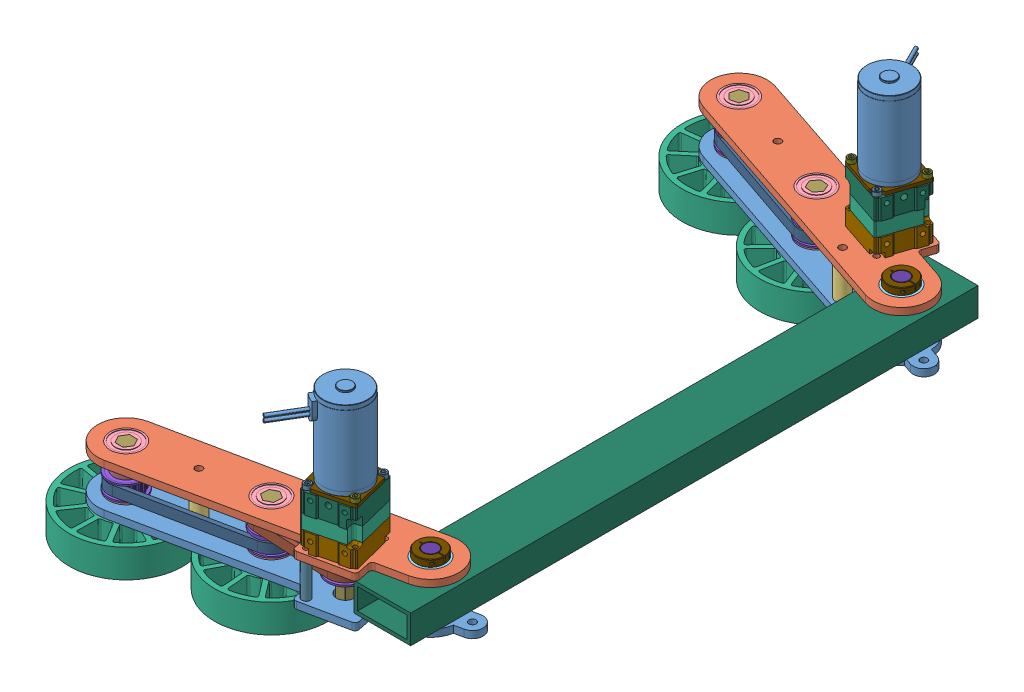
SolidWorks assembly IntakeV7Assem, configuration Default. Lengths in mm.
Overall size (333.6 194.94 656.15).
123 component instances, 36 part files, 159 mates.
Components (placement in the parent):
- IntakeV7PlateBottom-1: IntakeV7PlateBottom [Default] at (95.0249 -59.099 -418.9986) x (-0.203071 0 -0.979164) z (0.979164 0 -0.203071) size (67.49 6.35 297.21)
- IntakeV7PlateBottom-2: IntakeV7PlateBottom [Default] at (61.0398 -52.749 -268.9804) x (-0.317653 0 0.948207) z (0.948207 0 0.317653) size (67.49 6.35 297.21)
- IntakeV7PlateTop-1: IntakeV7PlateTop [Default] at (95.0249 -20.491 -418.9986) x (-0.203071 0 -0.979164) z (0.979164 0 -0.203071) size (67.49 6.35 281.33)
- IntakeV7PlateTop-2: IntakeV7PlateTop [Default] at (61.0398 -14.141 -268.9804) x (-0.317653 0 0.948207) z (0.948207 0 0.317653) size (67.49 6.35 281.33)
- PlateSpacer-1: PlateSpacer [Default] at (-344.9218 -20.491 -112.451) x (-0.978908 0 -0.204301) z (0 -1 0) size (12.7 12.7 32.26)
- PlateSpacer-2: PlateSpacer [Default] at (-227.8654 -20.491 -152.2919) x (1 0 0) z (0 -1 0) size (12.7 12.7 32.26)
- PlateSpacer-3: PlateSpacer [Default] at (-227.9763 -52.749 -572.0649) x (1 0 0) z (0 1 0) size (12.7 12.7 32.26)
- PlateSpacer-4: PlateSpacer [Default] at (-339.4879 -52.749 -625.4941) x (-0.769908 0 0.638155) z (0 1 0) size (12.7 12.7 32.26)
- HalfHexBearing-1: HalfHexBearing [Default] at (-398.7795 -14.141 -101.2813) x (0.520029 0 -0.854148) z (-0.854148 0 -0.520029) size (31.12 7.94 31.12)
- HalfHexBearing-2: HalfHexBearing [Default] at (-398.7795 -59.099 -101.2813) x (-0.520029 0 0.854148) z (-0.854148 0 -0.520029) size (31.12 7.94 31.12)
- HalfHexBearing-3: HalfHexBearing [Default] at (-291.0642 -14.141 -123.6206) x (-0.062031 0 0.998074) z (0.998074 0 0.062031) size (31.12 7.94 31.12)
- HalfHexBearing-4: HalfHexBearing [Default] at (-291.0642 -59.099 -123.6206) x (0.062031 0 -0.998074) z (0.998074 0 0.062031) size (31.12 7.94 31.12)
- HalfHexBearing-5: HalfHexBearing [Default] at (-391.6428 -14.141 -642.9662) x (-0.712674 0 -0.701495) z (-0.701495 0 0.712674) size (31.12 7.94 31.12)
- HalfHexBearing-6: HalfHexBearing [Default] at (-391.6428 -59.099 -642.9662) x (0.712674 0 0.701495) z (-0.701495 0 0.712674) size (31.12 7.94 31.12)
- HalfHexBearing-7: HalfHexBearing [Default] at (-287.333 -14.141 -608.022) x (-0.408462 0 -0.912775) z (-0.912775 0 0.408462) size (31.12 7.94 31.12)
- HalfHexBearing-8: HalfHexBearing [Default] at (-287.333 -59.099 -608.022) x (0.408462 0 0.912775) z (-0.912775 0 0.408462) size (31.12 7.94 31.12)
- HalfRoundBearing-1: HalfRoundBearing [Default] at (-173.0483 -14.141 -148.0962) x (0.837169 0 0.546944) z (0.546944 0 -0.837169) size (31.12 7.94 31.12)
- HalfRoundBearing-2: HalfRoundBearing [Default] at (-173.0483 -59.099 -148.0962) x (-0.997571 0 -0.069658) z (0.069658 0 -0.997571) size (31.12 7.94 31.12)
- HalfRoundBearing-3: HalfRoundBearing [Default] at (-173.0483 -59.099 -569.7362) x (-1 0 0) z (0 0 -1) size (31.12 7.94 31.12)
- HalfRoundBearing-4: HalfRoundBearing [Default] at (-173.0483 -14.141 -569.7362) x (0.837169 0 0.546944) z (0.546944 0 -0.837169) size (31.12 7.94 31.12)
- 4inCompliantWheel-1: 4inCompliantWheel [Default] at (-286.2135 -79.3385 -139.5879) x (0.062031 0 -0.998074) z (0 1 0) size (101.6 101.6 25.74)
  - 4IN Compliant Wheel FINAL Overmold-1: 4IN Compliant Wheel FINAL Overmold [Default] at (-16.2374 3.8509 18.652) size (101.6 101.6 25.74)
  - 2in Wheel Intergrated 0500 HEX Hub-1: 2in Wheel Intergrated 0500 HEX Hub [Default] at (-16.2374 3.8509 5.952) x (-1 0 0) z (0 0 -1) size (41.91 41.91 25.4)
- 4inCompliantWheel-2: 4inCompliantWheel [Default] at (-414.9228 -79.3385 -105.5092) x (-0.999729 0 -0.023285) z (0 1 0) size (101.6 101.6 25.74)
  - 4IN Compliant Wheel FINAL Overmold-1: 4IN Compliant Wheel FINAL Overmold [Default] at (-16.2374 3.8509 18.652) size (101.6 101.6 25.74)
  - 2in Wheel Intergrated 0500 HEX Hub-1: 2in Wheel Intergrated 0500 HEX Hub [Default] at (-16.2374 3.8509 5.952) x (-1 0 0) z (0 0 -1) size (41.91 41.91 25.4)
- 4inCompliantWheel-3: 4inCompliantWheel [Default] at (-408.3193 -79.3385 -642.3514) x (-0.96385 0 0.266447) z (0 1 0) size (101.6 101.6 25.74)
  - 4IN Compliant Wheel FINAL Overmold-1: 4IN Compliant Wheel FINAL Overmold [Default] at (-16.2374 3.8509 18.652) size (101.6 101.6 25.74)
  - 2in Wheel Intergrated 0500 HEX Hub-1: 2in Wheel Intergrated 0500 HEX Hub [Default] at (-16.2374 3.8509 5.952) x (-1 0 0) z (0 0 -1) size (41.91 41.91 25.4)
- 4inCompliantWheel-4: 4inCompliantWheel [Default] at (-299.972 -79.3385 -597.1252) x (-0.586256 0 0.810126) z (0 1 0) size (101.6 101.6 25.74)
  - 4IN Compliant Wheel FINAL Overmold-1: 4IN Compliant Wheel FINAL Overmold [Default] at (-16.2374 3.8509 18.652) size (101.6 101.6 25.74)
  - 2in Wheel Intergrated 0500 HEX Hub-1: 2in Wheel Intergrated 0500 HEX Hub [Default] at (-16.2374 3.8509 5.952) x (-1 0 0) z (0 0 -1) size (41.91 41.91 25.4)
- 18THTD9MMPulley-1: 18THTD9MMPulley [Default] at (-221.16 -29.4115 -119.9599) x (0.999849 0 0.017394) z (0 -1 0) size (32 32 14.5)
- 18THTD9MMPulley-2: 18THTD9MMPulley [Default] at (-217.4874 -29.4115 -603.3747) x (1 0 0) z (0 1 0) size (32 32 14.5)
- 18THTD9MMPulley-3: 18THTD9MMPulley [Default] at (-291.0642 -43.9115 -123.6206) x (0.746276 0 0.665636) z (0 -1 0) size (32 32 14.5)
- 18THTD9MMPulley-4: 18THTD9MMPulley [Default] at (-398.7795 -43.9115 -101.2813) x (-0.520029 0 0.854148) z (0 1 0) size (32 32 14.5)
- 18THTD9MMPulley-5: 18THTD9MMPulley [Default] at (-391.6428 -43.9115 -642.9662) x (1 0 0) z (0 1 0) size (32 32 14.5)
- 18THTD9MMPulley-6: 18THTD9MMPulley [Default] at (-287.333 -43.9115 -608.022) x (1 0 0) z (0 1 0) size (32 32 14.5)
- 18THTD9MMPulley-7: 18THTD9MMPulley [Default] at (-291.0642 -29.4115 -123.6206) x (0.20332 0 -0.979112) z (0 1 0) size (32 32 14.5)
- 18THTD9MMPulley-8: 18THTD9MMPulley [Default] at (-287.333 -29.4115 -608.022) x (1 0 0) z (0 1 0) size (32 32 14.5)
- VersaPlanetary_v2_Single_Stage_10_1_with_BAG-1: VersaPlanetary_v2_Single_Stage_10_1_with_BAG [Default] at (-215.7363 2.484 -98.4068) x (0 -1 0) z (0.969767 0 -0.244033) size (163.4 63.56 63.56)
  - 217-2625-026 Rev1-1: 217-2625-026 Rev1 [Default] at (-6.5 22.225 0) x (0 -1 0) z (-1 0 0) size (44.45 42 18.13)
  - 217-2742-001 Rev4-1: 217-2742-001 Rev4 [Default] at (0.2002 22.225 0) x (1 0 0) z (0 -0.092627 0.995701) size (7 28 28)
  - 217-2742-001 Rev4-2: 217-2742-001 Rev4 [Default] at (8.2002 22.225 0) size (7 28 28)
  - 217-2625-017 Rev1_9714K61-1: 217-2625-017 Rev1_9714K61 [Default] at (7.42 22.3002 -0.342) x (0 0.56703 0.823697) z (0 -0.823697 0.56703) size (28.51 4.98 30.18)
  - 217-2625-003 Rev1-1: 217-2625-003 Rev1 [Default] at (7.4478 22.225 0) x (0 -1 0) z (1 0 0) size (17 17 64.12)
  - 217-2625-018 Rev1_98541A410-1: 217-2625-018 Rev1_98541A410 [Default] at (-0.7046 22.225 0) x (1 0 0) z (0 -0.017452 0.999848) size (1 19.6 17.4)
  - 832-1750-Ring-Gear-Screw_SSA0832-0500ZC-1: 832-1750-Ring-Gear-Screw_SSA0832-0500ZC [Default] at (-30.7 4.725 -17.5) x (0 0.997447 0.071411) z (0 -0.071411 0.997447) size (6.73 48.51 6.73)
  - 832-1750-Ring-Gear-Screw_SSA0832-0500ZC-2: 832-1750-Ring-Gear-Screw_SSA0832-0500ZC [Default] at (-30.7 39.725 17.5) x (0 0.005929 0.999982) z (0 -0.999982 0.005929) size (6.73 48.51 6.73)
  - 217-2625-025 Rev1-1: 217-2625-025 Rev1 [Default] at (-23.2 22.225 0) x (0 -1 0) z (-1 0 0) size (44.45 42 18)
  - 217-4649-002 Rev1_SSA0832-0500ZC-1: 217-4649-002 Rev1_SSA0832-0500ZC [Default] at (-33.7 4.2645 17.9605) x (0 0.33842 -0.940995) z (0 0.940995 0.33842) size (6.73 16.76 6.73)
  - 217-4649-002 Rev1_SSA0832-0500ZC-2: 217-4649-002 Rev1_SSA0832-0500ZC [Default] at (-33.7 40.1855 -17.9605) x (0 -0.308932 -0.951084) z (0 0.951084 -0.308932) size (6.73 16.76 6.73)
  - 217-4649-006 Rev1_SSA0004-008BA-1: 217-4649-006 Rev1_SSA0004-008BA [Default] at (-30.7 22.225 12.5) x (0 0.5 -0.866025) z (0 -0.866025 -0.5) size (7 14 7)
  - 217-4649-006 Rev1_SSA0004-008BA-2: 217-4649-006 Rev1_SSA0004-008BA [Default] at (-30.7 22.225 -12.5) x (0 -0.5 0.866025) z (0 0.866025 0.5) size (7 14 7)
  - 217-2822-003 Rev4-1: 217-2822-003 Rev4 [Default] at (-32.2 22.225 0) x (0 -1 0) z (-1 0 0) size (42 42 4.8)
  - 217-3351 Rev2-1: 217-3351 Rev2 [Default] at (-33.7 22.225 0) x (0 0 1) z (1 0 0) size (59.11 59.11 84.5)
  - 217-2820 Rev1_Public-1: 217-2820 Rev1_Public [Default] at (-4.6546 22.225 0) x (0 -0.456494 0.889726) z (-1 0 0) size (39.26 38.9 17.4)
    - 217-2625-100-1: 217-2625-100 [Default] at origin size (39.26 38.9 12.7)
      - 217-2625-008 Rev1-1: 217-2625-008 Rev1 [Default] at origin size (34.7 34.7 4.7)
      - 217-2625-010 Rev1-1: 217-2625-010 Rev1 [Default] at (0 10.193 3.65) x (0.999813 0.019336 0) z (0 0 1) size (4 4 12)
      - 217-2625-010 Rev1-2: 217-2625-010 Rev1 [Default] at (8.691 -5.3258 3.65) size (4 4 12)
      - 217-2625-010 Rev1-3: 217-2625-010 Rev1 [Default] at (-8.691 -5.3258 3.65) size (4 4 12)
      - 217-2625-005 Rev1_Planet_Revolving_Follower01-1: 217-2625-005 Rev1_Planet_Revolving_Follower01 [Default] at (8.691 -5.3258 6.35) x (0.932816 0.360354 0) z (0 0 1) size (16.91 16.92 8)
      - 217-2625-005 Rev1_Planet_Revolving_Follower01-2: 217-2625-005 Rev1_Planet_Revolving_Follower01 [Default] at (-8.691 -5.3258 6.35) x (-0.932788 -0.360426 0) z (0 0 1) size (16.91 16.92 8)
      - 217-2625-005 Rev1_Planet_Revolving_Follower01-3: 217-2625-005 Rev1_Planet_Revolving_Follower01 [Default] at (0 10.193 6.35) x (0.893583 0.448898 0) z (0 0 1) size (16.91 16.92 8)
    - 217-2625-007 Rev1_Public-1: 217-2625-007 Rev1_Public [Default] at (0 0 6.7) x (0.992772 0.120019 0) z (0 0 1) size (14.49 14.49 12.72)
  - 217-2816-001 Rev1-1: 217-2816-001 Rev1 [Default] at (-6.35 22.225 0) x (0 -1 0) z (1 0 0) size (42 42 14.5)
  - 217-4649-001 Rev1-1: 217-4649-001 Rev1 [Default] at (-20.046 22.225 0) x (0 -1 0) z (1 0 0) size (18 18 13)
  - 217-4649-007 Rev1_94105A824-1: 217-4649-007 Rev1_94105A824 [Default] at (-25.521 22.225 -6.7835) x (-0.996104 -0.088191 0) z (0 0 -1) size (4.83 4.83 4.9)
  - 217-2625-011 Rev1-1: 217-2625-011 Rev1 [Default] at (-24.7818 22.225 0) x (0 0 1) z (0 -1 0) size (8.01 7.5 7.94)
- VersaPlanetary_v2_Single_Stage_10_1_with_BAG-2: VersaPlanetary_v2_Single_Stage_10_1_with_BAG [Default] at (-238.5613 2.484 -610.4345) x (0 -1 0) z (-0.317653 0 0.948207) size (163.4 63.56 63.56)
  - 217-2625-026 Rev1-1: 217-2625-026 Rev1 [Default] at (-6.5 22.225 0) x (0 -1 0) z (-1 0 0) size (44.45 42 18.13)
  - 217-2742-001 Rev4-1: 217-2742-001 Rev4 [Default] at (0.2002 22.225 0) x (1 0 0) z (0 -0.092627 0.995701) size (7 28 28)
  - 217-2742-001 Rev4-2: 217-2742-001 Rev4 [Default] at (8.2002 22.225 0) size (7 28 28)
  - 217-2625-017 Rev1_9714K61-1: 217-2625-017 Rev1_9714K61 [Default] at (7.42 22.3002 -0.342) x (0 0.56703 0.823697) z (0 -0.823697 0.56703) size (28.51 4.98 30.18)
  - 217-2625-003 Rev1-1: 217-2625-003 Rev1 [Default] at (7.4478 22.225 0) x (0 -1 0) z (1 0 0) size (17 17 64.12)
  - 217-2625-018 Rev1_98541A410-1: 217-2625-018 Rev1_98541A410 [Default] at (-0.7046 22.225 0) x (1 0 0) z (0 -0.017452 0.999848) size (1 19.6 17.4)
  - 832-1750-Ring-Gear-Screw_SSA0832-0500ZC-1: 832-1750-Ring-Gear-Screw_SSA0832-0500ZC [Default] at (-30.7 4.725 -17.5) x (0 0.997447 0.071411) z (0 -0.071411 0.997447) size (6.73 48.51 6.73)
  - 832-1750-Ring-Gear-Screw_SSA0832-0500ZC-2: 832-1750-Ring-Gear-Screw_SSA0832-0500ZC [Default] at (-30.7 39.725 17.5) x (0 0.005929 0.999982) z (0 -0.999982 0.005929) size (6.73 48.51 6.73)
  - 217-2625-025 Rev1-1: 217-2625-025 Rev1 [Default] at (-23.2 22.225 0) x (0 -1 0) z (-1 0 0) size (44.45 42 18)
  - 217-4649-002 Rev1_SSA0832-0500ZC-1: 217-4649-002 Rev1_SSA0832-0500ZC [Default] at (-33.7 4.2645 17.9605) x (0 0.33842 -0.940995) z (0 0.940995 0.33842) size (6.73 16.76 6.73)
  - 217-4649-002 Rev1_SSA0832-0500ZC-2: 217-4649-002 Rev1_SSA0832-0500ZC [Default] at (-33.7 40.1855 -17.9605) x (0 -0.308932 -0.951084) z (0 0.951084 -0.308932) size (6.73 16.76 6.73)
  - 217-4649-006 Rev1_SSA0004-008BA-1: 217-4649-006 Rev1_SSA0004-008BA [Default] at (-30.7 22.225 12.5) x (0 0.5 -0.866025) z (0 -0.866025 -0.5) size (7 14 7)
  - 217-4649-006 Rev1_SSA0004-008BA-2: 217-4649-006 Rev1_SSA0004-008BA [Default] at (-30.7 22.225 -12.5) x (0 -0.5 0.866025) z (0 0.866025 0.5) size (7 14 7)
  - 217-2822-003 Rev4-1: 217-2822-003 Rev4 [Default] at (-32.2 22.225 0) x (0 -1 0) z (-1 0 0) size (42 42 4.8)
  - 217-3351 Rev2-1: 217-3351 Rev2 [Default] at (-33.7 22.225 0) x (0 0 1) z (1 0 0) size (59.11 59.11 84.5)
  - 217-2820 Rev1_Public-1: 217-2820 Rev1_Public [Default] at (-4.6546 22.225 0) x (0 -0.456494 0.889726) z (-1 0 0) size (39.26 38.9 17.4)
    - 217-2625-100-1: 217-2625-100 [Default] at origin size (39.26 38.9 12.7)
      - 217-2625-008 Rev1-1: 217-2625-008 Rev1 [Default] at origin size (34.7 34.7 4.7)
      - 217-2625-010 Rev1-1: 217-2625-010 Rev1 [Default] at (0 10.193 3.65) x (0.999813 0.019336 0) z (0 0 1) size (4 4 12)
      - 217-2625-010 Rev1-2: 217-2625-010 Rev1 [Default] at (8.691 -5.3258 3.65) size (4 4 12)
      - 217-2625-010 Rev1-3: 217-2625-010 Rev1 [Default] at (-8.691 -5.3258 3.65) size (4 4 12)
      - 217-2625-005 Rev1_Planet_Revolving_Follower01-1: 217-2625-005 Rev1_Planet_Revolving_Follower01 [Default] at (8.691 -5.3258 6.35) x (0.932816 0.360354 0) z (0 0 1) size (16.91 16.92 8)
      - 217-2625-005 Rev1_Planet_Revolving_Follower01-2: 217-2625-005 Rev1_Planet_Revolving_Follower01 [Default] at (-8.691 -5.3258 6.35) x (-0.932788 -0.360426 0) z (0 0 1) size (16.91 16.92 8)
      - 217-2625-005 Rev1_Planet_Revolving_Follower01-3: 217-2625-005 Rev1_Planet_Revolving_Follower01 [Default] at (0 10.193 6.35) x (0.893583 0.448898 0) z (0 0 1) size (16.91 16.92 8)
    - 217-2625-007 Rev1_Public-1: 217-2625-007 Rev1_Public [Default] at (0 0 6.7) x (0.992772 0.120019 0) z (0 0 1) size (14.49 14.49 12.72)
  - 217-2816-001 Rev1-1: 217-2816-001 Rev1 [Default] at (-6.35 22.225 0) x (0 -1 0) z (1 0 0) size (42 42 14.5)
  - 217-4649-001 Rev1-1: 217-4649-001 Rev1 [Default] at (-20.046 22.225 0) x (0 -1 0) z (1 0 0) size (18 18 13)
  - 217-4649-007 Rev1_94105A824-1: 217-4649-007 Rev1_94105A824 [Default] at (-25.521 22.225 -6.7835) x (-0.996104 -0.088191 0) z (0 0 -1) size (4.83 4.83 4.9)
  - 217-2625-011 Rev1-1: 217-2625-011 Rev1 [Default] at (-24.7818 22.225 0) x (0 0 1) z (0 -1 0) size (8.01 7.5 7.94)
- BetweenWheelsBelt-1: BetweenWheelsBelt [Default] at (-398.7795 -43.9115 -101.2813) x (0.980136 0 -0.198324) z (0 -1 0) size (140.93 30.93 9)
- BetweenWheelsBelt-2: BetweenWheelsBelt [Default] at (-391.6428 -43.9115 -642.9662) x (0.946657 0 0.322244) z (0 1 0) size (140.93 30.93 9)
- WheelToGearboxBelt-1: WheelToGearboxBelt [Default] at (-221.16 -29.4115 -119.9599) x (-0.998632 0 -0.052297) z (0 1 0) size (100.93 30.93 9)
- WheelToGearboxBelt-2: WheelToGearboxBelt [Default] at (-287.5105 -29.4115 -607.5194) x (0.997794 0 0.066391) z (0 -1 0) size (100.93 30.93 9)
- WheelAxle-1: WheelAxle [Default] at (-391.6317 -86.0992 -642.9693) x (-0.251175 0 0.967942) z (-0.967942 0 -0.251175) size (14.66 71.96 12.7)
- WheelAxle-2: WheelAxle [Default] at (-287.3492 -86.0992 -608.0337) x (0.586256 0 -0.810126) z (0.810126 0 0.586256) size (14.66 71.96 12.7)
- WheelAxle-3: WheelAxle [Default] at (-291.0442 -86.0992 -123.6194) x (0.062031 0 -0.998074) z (0.998074 0 0.062031) size (14.66 71.96 12.7)
- WheelAxle-4: WheelAxle [Default] at (-398.7965 -86.0992 -101.2917) x (0.520029 0 -0.854148) z (0.854148 0 0.520029) size (14.66 71.96 12.7)
- FrontAxleSpacer-2: FrontAxleSpacer [Default] at (-398.7795 -36.6581 -101.2813) size (22.23 14.58 22.23)
- GearboxMountSpacers-1: GearboxMountSpacers [Default] at (-207.2209 -52.749 -141.1934) size (7.62 32.26 7.62)
- GearboxMountSpacers-2: GearboxMountSpacers [Default] at (-235.099 -52.749 -98.7263) size (7.62 32.26 7.62)
- GearboxMountSpacers-3: GearboxMountSpacers [Default] at (-206.1624 -52.749 -580.6392) size (7.62 32.26 7.62)
- GearboxMountSpacers-4: GearboxMountSpacers [Default] at (-228.8125 -52.749 -626.1102) size (7.62 32.26 7.62)
- ArmMountBar-1: ArmMountBar [Default] at (-173.0483 -36.62 -612.9162) size (50.8 25.4 508)
- PivotSpacer-1: PivotSpacer [Default] at (-173.0483 -22.0785 -148.0962) x (1 0 0) z (0 -1 0) size (19.05 19.05 3.68)
- PivotSpacer-2: PivotSpacer [Default] at (-173.0483 -22.0785 -569.7362) x (1 0 0) z (0 -1 0) size (19.05 19.05 3.68)
- FrontAxleSpacer-1: FrontAxleSpacer [Default] at (-391.6428 -36.6581 -642.9662) size (22.23 14.58 22.23)
- ArmPivotAxle-1: ArmPivotAxle [Default] at (-173.0483 -65.449 -148.0962) size (12.7 57.66 12.7)
- ArmPivotAxle-2: ArmPivotAxle [Default] at (-173.0483 -65.449 -569.7362) size (12.7 57.66 12.7)
- HalfRoundShaftCollar-1: HalfRoundShaftCollar [Default] at (-168.5329 -10.3639 -150.7118) x (1 0 0) z (0 -1 0) size (25.39 25.4 6.35)
- HalfRoundShaftCollar-2: HalfRoundShaftCollar [Default] at (-169.5026 -61.6719 -151.9248) x (0.955715 0 -0.294293) z (0 -1 0) size (25.39 25.4 6.35)
- HalfRoundShaftCollar-3: HalfRoundShaftCollar [Default] at (-168.5329 -10.3639 -572.3518) x (1 0 0) z (0 -1 0) size (25.39 25.4 6.35)
- HalfRoundShaftCollar-4: HalfRoundShaftCollar [Default] at (-169.3234 -61.6719 -573.3906) x (0.968711 0 -0.248193) z (0 -1 0) size (25.39 25.4 6.35)
Mates (geometry in assembly coordinates):
- Concentric1: concentric aligned: cylinder of IntakeV7PlateBottom-1 through (-398.7795 -52.749 -101.2813) axis (0 -1 0) radius 14.2748; cylinder of IntakeV7PlateTop-1 through (-398.7795 -14.141 -101.2813) axis (0 -1 0) radius 14.2748
- Concentric2: concentric aligned: cylinder of IntakeV7PlateBottom-1 through (-173.0483 -52.749 -148.0962) axis (0 -1 0) radius 14.2748; cylinder of IntakeV7PlateTop-1 through (-173.0483 -14.141 -148.0962) axis (0 -1 0) radius 14.2748
- Distance1: distance = 32.258 mm anti-aligned: plane of IntakeV7PlateTop-1 through (95.0249 -20.491 -418.9986) normal (0 -1 0); plane of IntakeV7PlateBottom-1 through (95.0249 -52.749 -418.9986) normal (0 1 0)
- Coincident2: coincident aligned: plane of IntakeV7PlateBottom-1 through (95.0249 -59.099 -418.9986) normal (0 -1 0); plane of IntakeV7PlateBottom-2 through (61.0398 -59.099 -268.9804) normal (0 -1 0)
- Concentric3: concentric aligned: cylinder of IntakeV7PlateBottom-2 through (-173.0483 -59.099 -569.7362) axis (0 1 0) radius 14.2748; cylinder of IntakeV7PlateTop-2 through (-173.0483 -20.491 -569.7362) axis (0 1 0) radius 14.2748
- Concentric4: concentric aligned: cylinder of IntakeV7PlateBottom-2 through (-391.6428 -59.099 -642.9662) axis (0 1 0) radius 14.2748; cylinder of IntakeV7PlateTop-2 through (-391.6428 -20.491 -642.9662) axis (0 1 0) radius 14.2748
- Coincident3: coincident aligned: plane of IntakeV7PlateTop-1 through (95.0249 -14.141 -418.9986) normal (0 1 0); plane of IntakeV7PlateTop-2 through (61.0398 -14.141 -268.9804) normal (0 1 0)
- Coincident4: coincident anti-aligned: plane of IntakeV7PlateTop-1 through (95.0249 -20.491 -418.9986) normal (0 -1 0); plane of PlateSpacer-1 through (-344.9218 -20.491 -112.451) normal (0 1 0)
- Coincident5: coincident anti-aligned: plane of IntakeV7PlateTop-1 through (95.0249 -20.491 -418.9986) normal (0 -1 0); plane of PlateSpacer-2 through (-227.8654 -20.491 -152.2919) normal (0 1 0)
- Coincident6: coincident anti-aligned: plane of IntakeV7PlateTop-2 through (61.0398 -20.491 -268.9804) normal (0 -1 0); plane of PlateSpacer-4 through (-339.4879 -20.491 -625.4941) normal (0 1 0)
- Coincident7: coincident anti-aligned: plane of IntakeV7PlateBottom-2 through (61.0398 -52.749 -268.9804) normal (0 1 0); plane of PlateSpacer-3 through (-227.9763 -52.749 -572.0649) normal (0 -1 0)
- Concentric9: concentric anti-aligned: cylinder of IntakeV7PlateTop-2 through (-391.6428 -20.491 -642.9662) axis (0 1 0) radius 14.2748; cylinder of HalfHexBearing-5 through (-391.6428 -14.141 -642.9662) axis (0 -1 0) radius 14.2748
- Coincident8: coincident anti-aligned: plane of IntakeV7PlateTop-2 through (61.0398 -20.491 -268.9804) normal (0 -1 0); plane of HalfHexBearing-5 through (-402.7302 -20.491 -653.8797) normal (0 1 0)
- Concentric10: concentric aligned: cylinder of IntakeV7PlateBottom-2 through (-391.6428 -59.099 -642.9662) axis (0 1 0) radius 14.2748; cylinder of HalfHexBearing-6 through (-391.6428 -59.099 -642.9662) axis (0 1 0) radius 14.2748
- Coincident9: coincident anti-aligned: plane of IntakeV7PlateBottom-2 through (61.0398 -52.749 -268.9804) normal (0 1 0); plane of HalfHexBearing-6 through (-380.5554 -52.749 -632.0527) normal (0 -1 0)
- Concentric11: concentric aligned: cylinder of IntakeV7PlateTop-1 through (-398.7795 -14.141 -101.2813) axis (0 -1 0) radius 14.2748; cylinder of HalfHexBearing-1 through (-398.7795 -14.141 -101.2813) axis (0 -1 0) radius 14.2748
- Concentric12: concentric anti-aligned: cylinder of IntakeV7PlateBottom-1 through (-398.7795 -52.749 -101.2813) axis (0 -1 0) radius 14.2748; cylinder of HalfHexBearing-2 through (-398.7795 -59.099 -101.2813) axis (0 1 0) radius 14.2748
- Coincident11: coincident anti-aligned: plane of IntakeV7PlateBottom-1 through (95.0249 -52.749 -418.9986) normal (0 1 0); plane of HalfHexBearing-2 through (-406.8698 -52.749 -87.9929) normal (0 -1 0)
- Concentric13: concentric aligned: cylinder of IntakeV7PlateTop-1 through (-291.0642 -14.141 -123.6206) axis (0 -1 0) radius 14.2748; cylinder of HalfHexBearing-3 through (-291.0642 -14.141 -123.6206) axis (0 -1 0) radius 14.2748
- Coincident12: coincident anti-aligned: plane of IntakeV7PlateTop-1 through (95.0249 -20.491 -418.9986) normal (0 -1 0); plane of HalfHexBearing-3 through (-292.0292 -20.491 -108.0931) normal (0 1 0)
- Concentric14: concentric anti-aligned: cylinder of IntakeV7PlateBottom-1 through (-291.0642 -52.749 -123.6206) axis (0 -1 0) radius 14.2748; cylinder of HalfHexBearing-4 through (-291.0642 -59.099 -123.6206) axis (0 1 0) radius 14.2748
- Coincident13: coincident anti-aligned: plane of IntakeV7PlateBottom-1 through (95.0249 -52.749 -418.9986) normal (0 1 0); plane of HalfHexBearing-4 through (-290.0991 -52.749 -139.1482) normal (0 -1 0)
- Concentric15: concentric anti-aligned: cylinder of IntakeV7PlateTop-2 through (-287.333 -20.491 -608.022) axis (0 1 0) radius 14.2748; cylinder of HalfHexBearing-7 through (-287.333 -14.141 -608.022) axis (0 -1 0) radius 14.2748
- Coincident14: coincident anti-aligned: plane of IntakeV7PlateTop-2 through (61.0398 -20.491 -268.9804) normal (0 -1 0); plane of HalfHexBearing-7 through (-293.6877 -20.491 -622.2225) normal (0 1 0)
- Concentric16: concentric aligned: cylinder of IntakeV7PlateBottom-2 through (-287.333 -59.099 -608.022) axis (0 1 0) radius 14.2748; cylinder of HalfHexBearing-8 through (-287.333 -59.099 -608.022) axis (0 1 0) radius 14.2748
- Coincident15: coincident anti-aligned: plane of IntakeV7PlateBottom-2 through (61.0398 -52.749 -268.9804) normal (0 1 0); plane of HalfHexBearing-8 through (-280.9784 -52.749 -593.8215) normal (0 -1 0)
- Coincident16: coincident aligned: plane of HalfHexBearing-7 through (-290.3327 -14.141 -614.7253) normal (-0.102649 0 0.994718); plane of HalfHexBearing-8 through (-283.0276 -59.099 -613.9715) normal (-0.102649 0 0.994718)
- Coincident17: coincident aligned: plane of HalfHexBearing-5 through (-396.8766 -14.141 -648.1179) normal (0.266447 0 0.96385); plane of HalfHexBearing-6 through (-389.7982 -59.099 -650.0747) normal (0.266447 0 0.96385)
- Coincident18: coincident aligned: plane of HalfHexBearing-1 through (-394.9604 -14.141 -107.5541) normal (-0.877433 0 0.479699); plane of HalfHexBearing-2 through (-391.4375 -59.099 -101.1103) normal (-0.877433 0 0.479699)
- Coincident19: coincident aligned: plane of HalfHexBearing-3 through (-291.5197 -14.141 -116.2909) normal (0.552757 0 -0.833342); plane of HalfHexBearing-4 through (-297.6397 -59.099 -120.3503) normal (0.552757 0 -0.833342)
- Concentric17: concentric aligned: cylinder of IntakeV7PlateTop-1 through (-173.0483 -14.141 -148.0962) axis (0 -1 0) radius 14.2748; cylinder of HalfRoundBearing-1 through (-173.0483 -14.141 -148.0962) axis (0 -1 0) radius 14.2875
- Coincident20: coincident anti-aligned: plane of IntakeV7PlateTop-1 through (95.0249 -20.491 -418.9986) normal (0 -1 0); plane of HalfRoundBearing-1 through (-160.024 -20.491 -139.5871) normal (0 1 0)
- Concentric18: concentric anti-aligned: cylinder of IntakeV7PlateBottom-1 through (-173.0483 -52.749 -148.0962) axis (0 -1 0) radius 14.2748; cylinder of HalfRoundBearing-2 through (-173.0483 -59.099 -148.0962) axis (0 1 0) radius 14.2875
- Concentric19: concentric anti-aligned: cylinder of IntakeV7PlateTop-2 through (-173.0483 -20.491 -569.7362) axis (0 1 0) radius 14.2748; cylinder of HalfRoundBearing-4 through (-173.0483 -14.141 -569.7362) axis (0 -1 0) radius 14.2875
- Coincident22: coincident anti-aligned: plane of IntakeV7PlateTop-2 through (61.0398 -20.491 -268.9804) normal (0 -1 0); plane of HalfRoundBearing-4 through (-160.024 -20.491 -561.2271) normal (0 1 0)
- Concentric20: concentric aligned: cylinder of IntakeV7PlateBottom-2 through (-173.0483 -59.099 -569.7362) axis (0 1 0) radius 14.2748; cylinder of HalfRoundBearing-3 through (-173.0483 -59.099 -569.7362) axis (0 1 0) radius 14.2875
- Coincident23: coincident anti-aligned: plane of IntakeV7PlateBottom-2 through (61.0398 -52.749 -268.9804) normal (0 1 0); plane of HalfRoundBearing-3 through (-188.6058 -52.749 -569.7362) normal (0 -1 0)
- Concentric21: concentric aligned: cylinder of HalfHexBearing-3 through (-291.0642 -14.141 -123.6206) axis (0 -1 0) radius 15.5575; cylinder of 4inCompliantWheel-1/4IN Compliant Wheel FINAL Overmold-1 through (-291.0642 -30.8903 -123.6206) axis (0 -1 0) radius 50.8
- Parallel1: parallel aligned: plane of HalfHexBearing-4 through (-297.1841 -59.099 -127.68) normal (0.998074 0 0.062031); plane of 4inCompliantWheel-1/2in Wheel Intergrated 0500 HEX Hub-1 through (-297.199 -86.0865 -127.6898) normal (0.998074 0 0.062031)
- Coincident26: coincident anti-aligned: plane of IntakeV7PlateBottom-1 through (95.0249 -52.749 -418.9986) normal (0 1 0); plane of HalfRoundBearing-2 through (-188.568 -52.749 -149.1799) normal (0 -1 0)
- Distance3: distance = 1.5875 mm anti-aligned: plane of 4inCompliantWheel-1/2in Wheel Intergrated 0500 HEX Hub-1 through (-293.5993 -60.6865 -123.7782) normal (0 1 0); plane of IntakeV7PlateBottom-1 through (95.0249 -59.099 -418.9986) normal (0 -1 0)
- Concentric22: concentric aligned: cylinder of HalfHexBearing-1 through (-398.7795 -14.141 -101.2813) axis (0 -1 0) radius 15.5575; cone of 4inCompliantWheel-2/2in Wheel Intergrated 0500 HEX Hub-1 through (-398.7795 -61.2128 -101.2813) axis (0 -1 0)
- Coincident28: coincident aligned: plane of 4inCompliantWheel-1/4IN Compliant Wheel FINAL Overmold-1 through (-316.9869 -86.0865 -125.2317) normal (0 -1 0); plane of 4inCompliantWheel-2/4IN Compliant Wheel FINAL Overmold-1 through (-399.3842 -86.0865 -75.3156) normal (0 -1 0)
- Concentric23: concentric aligned: cylinder of HalfHexBearing-5 through (-391.6428 -14.141 -642.9662) axis (0 -1 0) radius 15.5575; cone of 4inCompliantWheel-3/2in Wheel Intergrated 0500 HEX Hub-1 through (-391.6428 -61.2128 -642.9662) axis (0 -1 0)
- Coincident29: coincident aligned: plane of 4inCompliantWheel-1/4IN Compliant Wheel FINAL Overmold-1 through (-316.9869 -86.0865 -125.2317) normal (0 -1 0); plane of 4inCompliantWheel-3/4IN Compliant Wheel FINAL Overmold-1 through (-384.7224 -86.0865 -617.9323) normal (0 -1 0)
- Concentric24: concentric aligned: cylinder of HalfHexBearing-7 through (-287.333 -14.141 -608.022) axis (0 -1 0) radius 15.5575; cone of 4inCompliantWheel-4/2in Wheel Intergrated 0500 HEX Hub-1 through (-287.333 -61.2128 -608.022) axis (0 -1 0)
- Coincident30: coincident aligned: plane of 4inCompliantWheel-3/4IN Compliant Wheel FINAL Overmold-1 through (-384.7224 -86.0865 -617.9323) normal (0 -1 0); plane of 4inCompliantWheel-4/4IN Compliant Wheel FINAL Overmold-1 through (-266.2918 -86.0865 -592.7953) normal (0 -1 0)
- Parallel2: parallel aligned: plane of HalfHexBearing-8 through (-283.0276 -59.099 -613.9715) normal (-0.102649 0 0.994718); plane of 4inCompliantWheel-4/2in Wheel Intergrated 0500 HEX Hub-1 through (-283.0172 -86.0865 -613.9859) normal (-0.102649 0 0.994718)
- Parallel3: parallel aligned: plane of HalfHexBearing-6 through (-389.7982 -59.099 -650.0747) normal (0.266447 0 0.96385); plane of 4inCompliantWheel-3/2in Wheel Intergrated 0500 HEX Hub-1 through (-389.7937 -86.0865 -650.0919) normal (0.266447 0 0.96385)
- Parallel4: parallel aligned: plane of HalfHexBearing-2 through (-391.4375 -59.099 -101.1103) normal (-0.877433 0 0.479699); plane of 4inCompliantWheel-2/2in Wheel Intergrated 0500 HEX Hub-1 through (-391.4198 -86.0865 -101.1099) normal (-0.877433 0 0.479699)
- Concentric25: concentric anti-aligned: cylinder of HalfHexBearing-1 through (-398.7795 -14.141 -101.2813) axis (0 -1 0) radius 15.5575; cylinder of 18THTD9MMPulley-4 through (-398.7795 -43.9115 -101.2813) axis (0 1 0) radius 16
- Parallel5: parallel: plane of HalfHexBearing-2 through (-402.5542 -57.2575 -200.1233) normal (0.854148 0 0.520029); plane of 18THTD9MMPulley-4 through (-404.4552 -34.82 -196.9818) normal (0.854148 0 0.520029)
- Concentric26: concentric aligned: cylinder of HalfHexBearing-4 through (-291.0642 -59.099 -123.6206) axis (0 1 0) radius 15.5575; cylinder of 18THTD9MMPulley-3 through (-291.0642 -43.9115 -123.6206) axis (0 1 0) radius 16
- Parallel6: parallel: plane of HalfHexBearing-4; plane of 18THTD9MMPulley-3 through (-289.2053 -49.32 -165.898) normal (-0.313476 0 -0.949596)
- Concentric27: concentric aligned: cylinder of HalfHexBearing-3 through (-291.0642 -14.141 -123.6206) axis (0 -1 0) radius 15.5575; cylinder of 18THTD9MMPulley-7 through (-291.0642 -29.4115 -123.6206) axis (0 -1 0) radius 16
- Parallel7: parallel: plane of HalfHexBearing-3; plane of 18THTD9MMPulley-7 through (-297.4132 -20.32 -173.219) normal (0.979112 0 0.20332)
- Coincident37: coincident anti-aligned: circle of 18THTD9MMPulley-3; circle of 18THTD9MMPulley-7
- Coincident38: coincident anti-aligned: plane of HalfHexBearing-4 through (-290.6703 -51.1615 -129.9584) normal (0 1 0); plane of 18THTD9MMPulley-3 through (-291.0642 -51.1615 -123.6206) normal (0 -1 0)
- Concentric30: concentric anti-aligned: cylinder of HalfHexBearing-6 through (-391.6428 -59.099 -642.9662) axis (0 1 0) radius 15.5575; cylinder of 18THTD9MMPulley-5 through (-391.6428 -43.9115 -642.9662) axis (0 -1 0) radius 16
- Coincident39: coincident anti-aligned: plane of HalfHexBearing-6 through (-387.1173 -51.1615 -638.5117) normal (0 1 0); plane of 18THTD9MMPulley-5 through (-391.6428 -51.1615 -642.9662) normal (0 -1 0)
- Coincident41: coincident anti-aligned: plane of HalfHexBearing-8 through (-284.7393 -51.1615 -602.2259) normal (0 1 0); plane of 18THTD9MMPulley-6 through (-287.333 -51.1615 -608.022) normal (0 -1 0)
- Concentric31: concentric aligned: cylinder of HalfHexBearing-8 through (-287.333 -59.099 -608.022) axis (0 1 0) radius 15.5575; cylinder of 18THTD9MMPulley-6 through (-287.333 -43.9115 -608.022) axis (0 1 0) radius 16
- Coincident42: coincident anti-aligned: circle of 18THTD9MMPulley-6; circle of 18THTD9MMPulley-8
- Coincident43: coincident: plane of IntakeV7PlateTop-1 through (179.8685 -12.2995 -291.9749) normal (0 1 0); plane of VersaPlanetary_v2_Single_Stage_10_1_with_BAG-1/217-2625-026 Rev1-1 through (-245.7356 -12.2995 -167.2926) normal (0 -1 0)
- Concentric32: concentric: cylinder of IntakeV7PlateTop-1 through (-207.1867 -12.2995 -155.1664) axis (0 -1 0) radius 2.4892; cylinder of VersaPlanetary_v2_Single_Stage_10_1_with_BAG-1/217-2625-026 Rev1-1 through (-207.1867 4.3255 -155.1664) axis (0 1 0) radius 2.0193
- Concentric33: concentric: cylinder of IntakeV7PlateTop-1 through (-249.5011 -12.2995 -127.0572) axis (0 -1 0) radius 2.4892; cylinder of VersaPlanetary_v2_Single_Stage_10_1_with_BAG-1/217-2625-026 Rev1-1 through (-249.5011 4.3255 -127.0572) axis (0 1 0) radius 2.0193
- Concentric34: concentric: cylinder of 18THTD9MMPulley-1 through (-228.3439 -27.57 -141.1118) axis (0 1 0) radius 16; cylinder of VersaPlanetary_v2_Single_Stage_10_1_with_BAG-1/217-2625-003 Rev1-1 through (-228.3439 -52.8747 -141.1118) axis (0 -1 0) radius 2.5527
- Coincident46: coincident: plane of 18THTD9MMPulley-1 through (-230.3688 -34.82 -147.1303) normal (0.31889 0 0.947792); plane of VersaPlanetary_v2_Single_Stage_10_1_with_BAG-1/217-2625-003 Rev1-1 through (-233.8436 -52.8747 -145.9612) normal (-0.31889 0 -0.947792)
- Coincident47: coincident anti-aligned: plane of 18THTD9MMPulley-1 through (-221.16 -22.1615 -119.9599) normal (0 1 0); circle of 18THTD9MMPulley-7
- Coincident48: coincident anti-aligned: plane of IntakeV7PlateTop-1 through (95.0249 -20.491 -418.9986) normal (0 -1 0); plane of HalfHexBearing-1 through (-390.6891 -20.491 -114.5697) normal (0 1 0)
- Concentric35: concentric: cylinder of IntakeV7PlateTop-2 through (-227.7775 -18.6495 -580.2764) axis (0 1 0) radius 9.525; cylinder of VersaPlanetary_v2_Single_Stage_10_1_with_BAG-2/217-2625-003 Rev1-1 through (-227.7775 -52.8747 -580.2764) axis (0 -1 0) radius 2.5527
- Concentric36: concentric: cylinder of IntakeV7PlateTop-2 through (-207.572 -18.6495 -564.885) axis (0 1 0) radius 2.4892; cylinder of VersaPlanetary_v2_Single_Stage_10_1_with_BAG-2/217-2625-026 Rev1-1 through (-207.572 4.3255 -564.885) axis (0 1 0) radius 2.0193
- Coincident49: coincident: plane of IntakeV7PlateTop-2 through (169.8416 -12.2995 -403.3696) normal (0 1 0); plane of VersaPlanetary_v2_Single_Stage_10_1_with_BAG-2/217-2625-026 Rev1-1 through (-208.7316 -12.2995 -605.2795) normal (0 -1 0)
- Concentric37: concentric anti-aligned: cylinder of IntakeV7PlateBottom-2 through (-217.4874 -59.099 -603.3747) axis (0 1 0) radius 7.9375; cylinder of 18THTD9MMPulley-2 through (-217.4874 -29.4115 -603.3747) axis (0 -1 0) radius 16
- Coincident51: coincident aligned: plane of 18THTD9MMPulley-2 through (-217.4874 -22.1615 -603.3747) normal (0 1 0); plane of 18THTD9MMPulley-8 through (-287.333 -22.1615 -608.022) normal (0 1 0)
- Concentric38: concentric anti-aligned: cylinder of IntakeV7PlateTop-1 through (-398.7795 -14.141 -101.2813) axis (0 -1 0) radius 25.4; cylinder of BetweenWheelsBelt-1 through (-398.7795 -48.4115 -101.2813) axis (0 1 0) radius 11.657
- Width1: width anti-aligned: plane of 18THTD9MMPulley-4 through (-398.7795 -49.4115 -101.2813) normal (0 1 0); plane of 18THTD9MMPulley-4 through (-398.7795 -38.4115 -101.2813) normal (0 -1 0); plane of BetweenWheelsBelt-1 through (-398.7795 -48.4115 -101.2813) normal (0 -1 0); plane of BetweenWheelsBelt-1 through (-398.7795 -39.4115 -101.2813) normal (0 1 0)
- Coincident53: coincident anti-aligned: plane of HalfHexBearing-2 through (-402.0816 -51.1615 -95.8575) normal (0 1 0); plane of 18THTD9MMPulley-4 through (-398.7795 -51.1615 -101.2813) normal (0 -1 0)
- Parallel8: parallel anti-aligned: cylinder of 18THTD9MMPulley-3 through (-291.0642 -43.9115 -123.6206) axis (0 -1 0) radius 16; cylinder of BetweenWheelsBelt-1 through (-290.9644 -48.4115 -123.097) axis (0 1 0) radius 15.467
- Concentric40: concentric anti-aligned: cylinder of IntakeV7PlateBottom-2 through (-391.6428 -59.099 -642.9662) axis (0 1 0) radius 25.4; cylinder of BetweenWheelsBelt-2 through (-391.6428 -39.4115 -642.9662) axis (0 -1 0) radius 11.657
- Width2: width aligned: plane of BetweenWheelsBelt-2 through (-391.6428 -39.4115 -642.9662) normal (0 1 0); plane of BetweenWheelsBelt-2 through (-391.6428 -48.4115 -642.9662) normal (0 -1 0); plane of 18THTD9MMPulley-5 through (-391.6428 -49.4115 -642.9662) normal (0 1 0); plane of 18THTD9MMPulley-5 through (-391.6428 -38.4115 -642.9662) normal (0 -1 0)
- Tangent1: tangent aligned: cylinder of 18THTD9MMPulley-6 through (-287.333 -43.9115 -608.022) axis (0 1 0) radius 16; cylinder of BetweenWheelsBelt-2 through (-287.5105 -39.4115 -607.5194) axis (0 -1 0) radius 15.467
- Concentric43: concentric anti-aligned: cylinder of BetweenWheelsBelt-2 through (-287.5105 -39.4115 -607.5194) axis (0 -1 0) radius 15.467; cylinder of WheelToGearboxBelt-2 through (-287.5105 -33.9115 -607.5194) axis (0 1 0) radius 15.467
- Width3: width anti-aligned: plane of WheelToGearboxBelt-2 through (-287.5105 -33.9115 -607.5194) normal (0 -1 0); plane of WheelToGearboxBelt-2 through (-287.5105 -24.9115 -607.5194) normal (0 1 0); plane of 18THTD9MMPulley-8 through (-287.333 -34.9115 -608.022) normal (0 1 0); plane of 18THTD9MMPulley-8 through (-287.333 -23.9115 -608.022) normal (0 -1 0)
- Tangent3: tangent aligned: cylinder of 18THTD9MMPulley-2 through (-217.4874 -29.4115 -603.3747) axis (0 -1 0) radius 16; cylinder of WheelToGearboxBelt-2 through (-217.665 -33.9115 -602.872) axis (0 1 0) radius 15.467
- Concentric46: concentric anti-aligned: cylinder of 18THTD9MMPulley-7 through (-291.0642 -29.4115 -123.6206) axis (0 1 0) radius 16; cylinder of WheelToGearboxBelt-1 through (-291.0642 -24.9115 -123.6206) axis (0 -1 0) radius 11.657
- Concentric47: concentric anti-aligned: cylinder of 18THTD9MMPulley-1 through (-221.16 -29.4115 -119.9599) axis (0 1 0) radius 16; cylinder of WheelToGearboxBelt-1 through (-221.16 -24.9115 -119.9599) axis (0 -1 0) radius 15.467
- Width4: width anti-aligned: plane of WheelToGearboxBelt-1 through (-221.16 -24.9115 -119.9599) normal (0 1 0); plane of WheelToGearboxBelt-1 through (-221.16 -33.9115 -119.9599) normal (0 -1 0); plane of 18THTD9MMPulley-1 through (-221.16 -23.9115 -119.9599) normal (0 -1 0); plane of 18THTD9MMPulley-1 through (-221.16 -34.9115 -119.9599) normal (0 1 0)
- Coincident55: coincident anti-aligned: plane of HalfHexBearing-5 through (-384.5644 -14.141 -644.9229) normal (-0.967942 0 -0.251175); plane of WheelAxle-1 through (-386.4061 -14.141 -637.8257) normal (0.967942 0 0.251175)
- Coincident56: coincident anti-aligned: plane of HalfHexBearing-5 through (-389.7982 -14.141 -650.0747) normal (-0.701495 0 0.712674); plane of WheelAxle-1 through (-384.5644 -14.141 -644.9229) normal (0.701495 0 -0.712674)
- Coincident57: coincident aligned: plane of HalfHexBearing-5 through (-398.5215 -14.141 -649.737) normal (0 1 0); plane of WheelAxle-1 through (-391.6317 -14.141 -642.9693) normal (0 1 0)
- Coincident58: coincident anti-aligned: plane of HalfHexBearing-7 through (-291.6384 -14.141 -602.0725) normal (0.912775 0 -0.408462); plane of WheelAxle-2 through (-294.6428 -14.141 -608.7864) normal (-0.912775 0 0.408462)
- Coincident59: coincident anti-aligned: plane of HalfHexBearing-7 through (-290.3327 -14.141 -614.7253) normal (-0.102649 0 0.994718); plane of WheelAxle-2 through (-283.0506 -14.141 -613.9739) normal (0.102649 0 -0.994718)
- Coincident60: coincident aligned: plane of HalfHexBearing-7 through (-291.2755 -14.141 -616.8321) normal (0 1 0); plane of WheelAxle-2 through (-287.3492 -14.141 -608.0337) normal (0 1 0)
- Coincident61: coincident anti-aligned: plane of HalfHexBearing-1 through (-402.5985 -14.141 -95.0085) normal (0.877433 0 -0.479699); plane of WheelAxle-4 through (-406.1269 -14.141 -101.4624) normal (-0.877433 0 0.479699)
- Coincident62: coincident anti-aligned: plane of HalfHexBearing-1 through (-402.3023 -14.141 -107.7251) normal (-0.023285 0 0.999729); plane of WheelAxle-4 through (-394.9835 -14.141 -107.5546) normal (0.023285 0 -0.999729)
- Coincident63: coincident aligned: plane of HalfHexBearing-1 through (-393.7601 -14.141 -109.5256) normal (0 1 0); plane of WheelAxle-4 through (-398.7965 -14.141 -101.2917) normal (0 1 0)
- Coincident64: coincident anti-aligned: plane of HalfHexBearing-3 through (-284.9442 -14.141 -119.5612) normal (-0.445317 0 -0.895373); plane of WheelAxle-3 through (-291.499 -14.141 -116.3012) normal (0.445317 0 0.895373)
- Coincident66: coincident anti-aligned: plane of HalfHexBearing-3 through (-290.6086 -14.141 -130.9504) normal (-0.552757 0 0.833342); plane of WheelAxle-3 through (-284.479 -14.141 -126.8846) normal (0.552757 0 -0.833342)
- Coincident67: coincident aligned: plane of HalfHexBearing-3 through (-291.6629 -14.141 -113.9872) normal (0 1 0); plane of WheelAxle-3 through (-291.0442 -14.141 -123.6194) normal (0 1 0)
- Coincident68: coincident anti-aligned: plane of HalfHexBearing-5 through (-396.1683 -22.0785 -647.4207) normal (0 -1 0); plane of FrontAxleSpacer-1 through (-391.6428 -22.0785 -642.9662) normal (0 1 0)
- Concentric49: concentric aligned: cylinder of 18THTD9MMPulley-5 through (-391.6428 -43.9115 -642.9662) axis (0 -1 0) radius 16; cylinder of FrontAxleSpacer-1 through (-391.6428 -22.0785 -642.9662) axis (0 -1 0) radius 11.1125
- Coincident69: coincident anti-aligned: plane of HalfHexBearing-1 through (-395.4773 -22.0785 -106.7052) normal (0 -1 0); plane of FrontAxleSpacer-2 through (-398.7795 -22.0785 -101.2813) normal (0 1 0)
- Concentric50: concentric aligned: cylinder of 18THTD9MMPulley-4 through (-398.7795 -43.9115 -101.2813) axis (0 -1 0) radius 16; cylinder of FrontAxleSpacer-2 through (-398.7795 -22.0785 -101.2813) axis (0 -1 0) radius 11.1125
- Concentric51: concentric anti-aligned: cylinder of IntakeV7PlateBottom-1 through (-227.8654 -52.749 -152.2919) axis (0 -1 0) radius 3.175; cylinder of PlateSpacer-2 through (-227.8654 -52.749 -152.2919) axis (0 1 0) radius 3.175
- Concentric53: concentric anti-aligned: cylinder of IntakeV7PlateBottom-1 through (-344.9218 -52.749 -112.451) axis (0 -1 0) radius 3.175; cylinder of PlateSpacer-1 through (-344.9218 -52.749 -112.451) axis (0 1 0) radius 3.175
- Concentric54: concentric anti-aligned: cylinder of IntakeV7PlateBottom-2 through (-227.9763 -59.099 -572.0649) axis (0 1 0) radius 3.175; cylinder of PlateSpacer-3 through (-227.9763 -20.491 -572.0649) axis (0 -1 0) radius 3.175
- Concentric55: concentric anti-aligned: cylinder of IntakeV7PlateTop-2 through (-339.4879 -20.491 -625.4941) axis (0 1 0) radius 3.175; cylinder of PlateSpacer-4 through (-339.4879 -20.491 -625.4941) axis (0 -1 0) radius 3.175
- Concentric56: concentric aligned: cylinder of IntakeV7PlateBottom-1 through (-235.099 -52.749 -98.7263) axis (0 -1 0) radius 2.4892; cylinder of GearboxMountSpacers-2 through (-235.099 -20.491 -98.7263) axis (0 -1 0) radius 2.4892
- Coincident70: coincident anti-aligned: plane of IntakeV7PlateTop-1 through (95.0249 -20.491 -418.9986) normal (0 -1 0); plane of GearboxMountSpacers-2 through (-235.099 -20.491 -98.7263) normal (0 1 0)
- Concentric57: concentric aligned: cylinder of IntakeV7PlateBottom-1 through (-207.2209 -52.749 -141.1934) axis (0 -1 0) radius 2.4892; cylinder of GearboxMountSpacers-1 through (-207.2209 -20.491 -141.1934) axis (0 -1 0) radius 2.4892
- Coincident71: coincident anti-aligned: plane of IntakeV7PlateBottom-1 through (95.0249 -52.749 -418.9986) normal (0 1 0); plane of GearboxMountSpacers-1 through (-207.2209 -52.749 -141.1934) normal (0 -1 0)
- Concentric58: concentric anti-aligned: cylinder of IntakeV7PlateBottom-2 through (-206.1624 -59.099 -580.6392) axis (0 1 0) radius 2.4892; cylinder of GearboxMountSpacers-3 through (-206.1624 -20.491 -580.6392) axis (0 -1 0) radius 2.4892
- Coincident72: coincident anti-aligned: plane of IntakeV7PlateTop-2 through (61.0398 -20.491 -268.9804) normal (0 -1 0); plane of GearboxMountSpacers-3 through (-206.1624 -20.491 -580.6392) normal (0 1 0)
- Concentric59: concentric anti-aligned: cylinder of IntakeV7PlateBottom-2 through (-228.8125 -59.099 -626.1102) axis (0 1 0) radius 2.4892; cylinder of GearboxMountSpacers-4 through (-228.8125 -20.491 -626.1102) axis (0 -1 0) radius 2.4892
- Coincident73: coincident anti-aligned: plane of IntakeV7PlateTop-2 through (61.0398 -20.491 -268.9804) normal (0 -1 0); plane of GearboxMountSpacers-4 through (-228.8125 -20.491 -626.1102) normal (0 1 0)
- Concentric60: concentric anti-aligned: cylinder of HalfRoundBearing-1 through (-173.0483 -14.141 -148.0962) axis (0 -1 0) radius 6.35; cylinder of ArmMountBar-1 through (-173.0483 -49.32 -148.0962) axis (0 1 0) radius 6.35
- Coincident74: coincident: plane of HalfRoundBearing-2 through (-185.7174 -49.32 -148.9808) normal (0 1 0); plane of ArmMountBar-1 through (-185.7483 -49.32 -104.9162) normal (0 -1 0)
- Concentric61: concentric aligned: cylinder of HalfRoundBearing-3 through (-173.0483 -59.099 -569.7362) axis (0 1 0) radius 6.35; cylinder of ArmMountBar-1 through (-173.0483 -49.32 -569.7362) axis (0 1 0) radius 6.35
- Concentric62: concentric anti-aligned: cylinder of HalfRoundBearing-4 through (-173.0483 -14.141 -569.7362) axis (0 -1 0) radius 6.35; cylinder of PivotSpacer-2 through (-173.0483 -25.7615 -569.7362) axis (0 1 0) radius 6.35
- Coincident75: coincident anti-aligned: plane of HalfRoundBearing-4 through (-167.7323 -22.0785 -566.2631) normal (0 -1 0); plane of PivotSpacer-2 through (-173.0483 -22.0785 -569.7362) normal (0 1 0)
- Concentric63: concentric anti-aligned: cylinder of HalfRoundBearing-1 through (-173.0483 -14.141 -148.0962) axis (0 -1 0) radius 6.35; cylinder of PivotSpacer-1 through (-173.0483 -25.7615 -148.0962) axis (0 1 0) radius 6.35
- Coincident76: coincident anti-aligned: plane of HalfRoundBearing-1 through (-167.7323 -22.0785 -144.6231) normal (0 -1 0); plane of PivotSpacer-1 through (-173.0483 -22.0785 -148.0962) normal (0 1 0)
- Tangent5: tangent aligned: cylinder of 18THTD9MMPulley-3 through (-291.0642 -43.9115 -123.6206) axis (0 1 0) radius 16; cylinder of BetweenWheelsBelt-1 through (-290.9644 -48.4115 -123.097) axis (0 1 0) radius 15.467
- Concentric66: concentric aligned: cylinder of HalfRoundBearing-1 through (-173.0483 -14.141 -148.0962) axis (0 -1 0) radius 6.35; cylinder of ArmPivotAxle-1 through (-173.0483 -7.791 -148.0962) axis (0 -1 0) radius 6.35
- Width5: width anti-aligned: plane of ArmPivotAxle-1 through (-173.0483 -7.791 -148.0962) normal (0 1 0); plane of ArmPivotAxle-1 through (-173.0483 -65.449 -148.0962) normal (0 -1 0); plane of HalfRoundBearing-2 through (-187.3011 -59.099 -149.0914) normal (0 -1 0); plane of HalfRoundBearing-1 through (-161.0872 -14.141 -140.2817) normal (0 1 0)
- Concentric67: concentric aligned: cylinder of HalfRoundBearing-4 through (-173.0483 -14.141 -569.7362) axis (0 -1 0) radius 6.35; cylinder of ArmPivotAxle-2 through (-173.0483 -7.791 -569.7362) axis (0 -1 0) radius 6.35
- Width6: width anti-aligned: plane of ArmPivotAxle-2 through (-173.0483 -7.791 -569.7362) normal (0 1 0); plane of ArmPivotAxle-2 through (-173.0483 -65.449 -569.7362) normal (0 -1 0); plane of HalfRoundBearing-3 through (-187.3358 -59.099 -569.7362) normal (0 -1 0); plane of HalfRoundBearing-4 through (-161.0872 -14.141 -561.9217) normal (0 1 0)
- Concentric68: concentric anti-aligned: cylinder of ArmPivotAxle-1 through (-173.0483 -7.791 -148.0962) axis (0 -1 0) radius 6.35; cylinder of HalfRoundShaftCollar-1 through (-173.0483 -14.141 -148.0962) axis (0 1 0) radius 6.477
- Coincident77: coincident anti-aligned: plane of HalfRoundBearing-1 through (-161.0872 -14.141 -140.2817) normal (0 1 0); plane of HalfRoundShaftCollar-1 through (-173.0483 -14.141 -148.0962) normal (0 -1 0)
- Concentric69: concentric anti-aligned: cylinder of ArmPivotAxle-1 through (-173.0483 -7.791 -148.0962) axis (0 -1 0) radius 6.35; cylinder of HalfRoundShaftCollar-2 through (-173.0483 -65.449 -148.0962) axis (0 1 0) radius 6.477
- Coincident78: coincident anti-aligned: plane of IntakeV7PlateBottom-1 through (95.0249 -59.099 -418.9986) normal (0 -1 0); plane of HalfRoundShaftCollar-2 through (-173.0483 -59.099 -148.0962) normal (0 1 0)
- Concentric70: concentric anti-aligned: cylinder of ArmPivotAxle-2 through (-173.0483 -7.791 -569.7362) axis (0 -1 0) radius 6.35; cylinder of HalfRoundShaftCollar-3 through (-173.0483 -14.141 -569.7362) axis (0 1 0) radius 6.477
- Coincident79: coincident anti-aligned: plane of HalfRoundBearing-4 through (-161.0872 -14.141 -561.9217) normal (0 1 0); plane of HalfRoundShaftCollar-3 through (-173.0483 -14.141 -569.7362) normal (0 -1 0)
- Concentric71: concentric anti-aligned: cylinder of ArmPivotAxle-2 through (-173.0483 -7.791 -569.7362) axis (0 -1 0) radius 6.35; cylinder of HalfRoundShaftCollar-4 through (-173.0483 -65.449 -569.7362) axis (0 1 0) radius 6.477
- Coincident80: coincident anti-aligned: plane of HalfRoundBearing-3 through (-187.3358 -59.099 -569.7362) normal (0 -1 0); plane of HalfRoundShaftCollar-4 through (-173.0483 -59.099 -569.7362) normal (0 1 0)
- Concentric72: concentric aligned: cylinder of ? through (-147.2605 -63.798 -275.5951) axis (0 0 1) radius 2.413; cylinder of ? through (-147.2605 -63.798 -262.8951) axis (0 0 1) radius 2.413
- Parallel9: parallel anti-aligned: plane of ? through (-152.8485 -67.735 -297.9471) normal (0 -1 0); plane of ? through (-151.9595 -59.099 -137.4191) normal (0 1 0)
- LimitDistance1: limit distance = 50.8 mm anti-aligned: plane of ? through (-147.3904 -63.798 -162.8122) normal (0 0 1); plane of ? through (-147.3904 -63.798 -162.8122) normal (0 0 -1)
- Parallel10: parallel aligned: plane of ArmMountBar-1 through (-185.7483 -23.92 -104.9162) normal (0 1 0); plane of ? through (-154.8873 -58.0195 -439.1802) normal (0 1 0)
- Angle3: planar angle = 1.27409 rad aligned: line of IntakeV7PlateTop-1 through (-396.0713 -12.2995 -211.7522) axis (0.985872 0 0.167502); line of ArmMountBar-1 through (-185.7483 -23.92 -104.9162) axis (0 0 -1)
- Angle4: planar angle = 1.867502 rad aligned: line of IntakeV7PlateTop-2 through (-398.099 -12.2995 -513.669) axis (0.990979 0 -0.134021); line of ArmMountBar-1 through (-185.7483 -23.92 -104.9162) axis (0 0 -1)
- Distance4: distance = 6.35 mm anti-aligned: plane of ? through (-153.9983 -57.2575 -278.6522) normal (-1 0 0); plane of ArmMountBar-1 through (-160.3483 -49.32 -104.9162) normal (1 0 0)
- Coincident82: coincident anti-aligned: plane of IntakeV7PlateBottom-1 through (175.2787 -59.099 -302.756) normal (0 -1 0); plane of ? through (-151.9595 -59.099 -137.4191) normal (0 1 0)
- Coincident83: coincident anti-aligned: plane of ? through (-147.2605 -63.798 -161.2951) normal (0 0 1); plane of ? through (-147.2605 -63.798 -161.2951) normal (0 0 -1)
- Width7: width anti-aligned: plane of ArmMountBar-1 through (-173.0483 -36.62 -104.9162) normal (0 0 1); plane of ArmMountBar-1 through (-173.0483 -36.62 -612.9162) normal (0 0 -1); plane of ? through (-149.2993 -61.9565 -439.1802) normal (0 0 -1); plane of ? through (-149.2993 -61.9565 -278.6522) normal (0 0 1)
- Width8: width anti-aligned: plane of IntakeV7PlateTop-1 through (95.0249 -20.491 -418.9986) normal (0 -1 0); plane of IntakeV7PlateBottom-1 through (95.0249 -52.749 -418.9986) normal (0 1 0); plane of ArmMountBar-1 through (-198.4483 -23.92 -104.9162) normal (0 1 0); plane of ArmMountBar-1 through (-198.4483 -49.32 -104.9162) normal (0 -1 0)
- Coincident84: coincident anti-aligned: plane of ? through (2205.3304 1880.1486 -148.7884) normal (0 0 -1); plane of ? through (2205.3304 1880.1486 -148.7884) normal (0 0 1)
- Parallel11: parallel anti-aligned: plane of ? through (2200.6314 1884.8476 -124.9124) normal (0 1 0); plane of ? through (2199.7424 1876.2116 -285.4404) normal (0 -1 0)
- Concentric73: concentric aligned: cylinder of ? through (2205.3304 1880.1486 -250.3884) axis (0 0 1) radius 2.413; cylinder of ? through (2205.3304 1880.1486 -263.0884) axis (0 0 1) radius 2.413
- LimitDistance2: limit distance = 50.8 mm: plane of ? through (2108.1919 1943.509 20.1684) normal (0 0 1); plane of ? through (2108.1919 1943.509 20.1684) normal (0 0 -1)
- Concentric76: concentric anti-aligned: circle of IntakeV7PlateTop-1; cylinder of 18THTD9MMPulley-1 through (-221.16 -29.4115 -119.9599) axis (0 -1 0) radius 16
- Concentric77: concentric anti-aligned: circle of 18THTD9MMPulley-1; circle of VersaPlanetary_v2_Single_Stage_10_1_with_BAG-1/217-2625-003 Rev1-1
- Tangent6: tangent aligned: plane of VersaPlanetary_v2_Single_Stage_10_1_with_BAG-1/217-2625-026 Rev1-1 through (-224.4722 3.984 -97.4717) normal (0.244033 0 0.969767); cylinder of GearboxMountSpacers-2 through (-235.099 -20.491 -98.7263) axis (0 -1 0) radius 3.81
- Concentric78: concentric aligned: circle of IntakeV7PlateTop-2; circle of 18THTD9MMPulley-2
- Concentric79: concentric aligned: circle of IntakeV7PlateTop-2; cylinder of VersaPlanetary_v2_Single_Stage_10_1_with_BAG-2/217-2625-003 Rev1-1 through (-217.4874 -54.7162 -603.3747) axis (0 -1 0) radius 2.5527
- Parallel13: parallel aligned: plane of IntakeV7PlateTop-2 through (-267.0515 -20.491 -378.8922) normal (0.948207 0 0.317653); plane of VersaPlanetary_v2_Single_Stage_10_1_with_BAG-2/217-2625-026 Rev1-1 through (-194.8115 3.984 -604.9533) normal (0.948207 0 0.317653)
- Coincident88: coincident anti-aligned: plane of VersaPlanetary_v2_Single_Stage_10_1_with_BAG-2/217-2625-026 Rev1-1 through (-203.4734 -14.141 -575.2409) normal (0 -1 0); line of IntakeV7PlateTop-2 through (-399.7112 -14.141 -618.8817) axis (0.948207 0 0.317653)
- Coincident89: coincident anti-aligned: plane of IntakeV7PlateTop-1 through (95.0249 -14.141 -418.9986) normal (0 1 0); plane of VersaPlanetary_v2_Single_Stage_10_1_with_BAG-1/217-2625-026 Rev1-1 through (-205.0305 -14.141 -146.9366) normal (0 -1 0)
